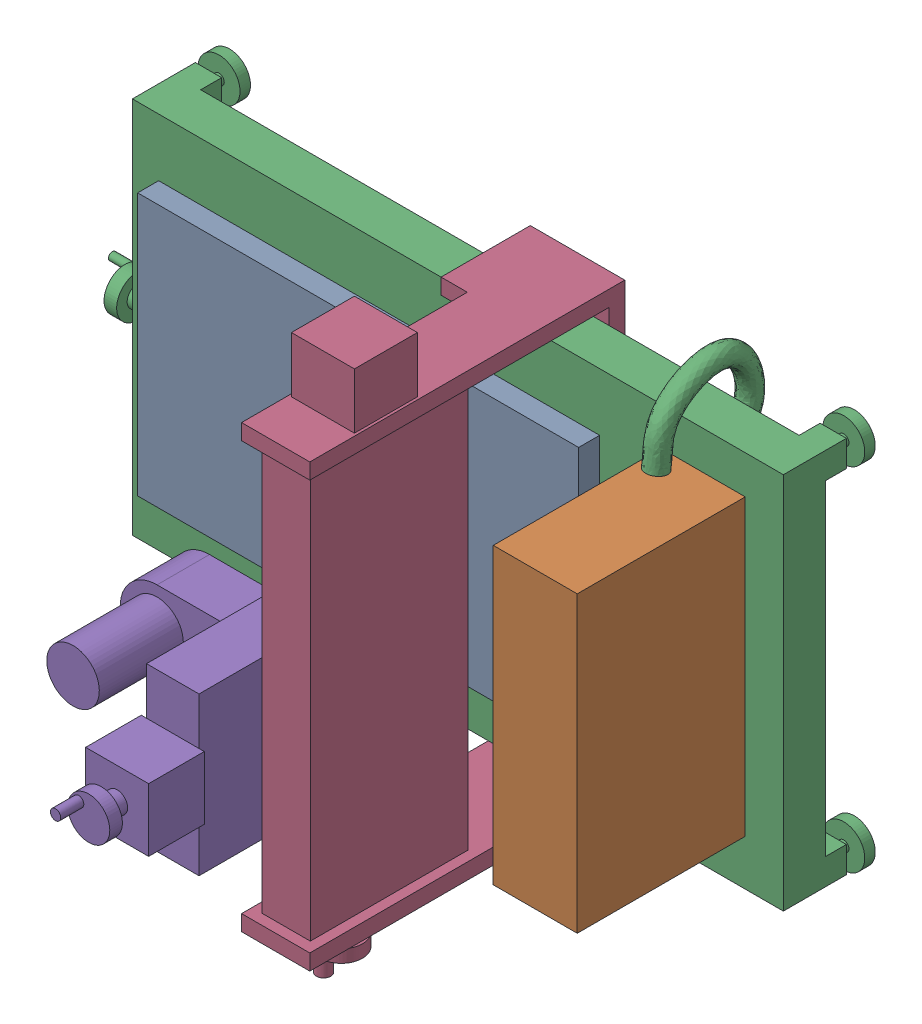
SolidWorks assembly RZ420, configuration ﾃﾞﾌｫﾙﾄ. Lengths in mm.
Overall size (727.03 522 505.06).
5 component instances, 5 part files, 12 mates.
Components (placement in the parent):
- base_RZ420-1: base_RZ420 [ﾃﾞﾌｫﾙﾄ] at (-219.6241 -100.9703 0) size (420 250 20)
- computer_RZ420-1: computer_RZ420 [ﾃﾞﾌｫﾙﾄ] at (259.0566 167.601 160) x (0 0 -1) z (0 -1 0) size (160 80 280)
- Part2_RZ420-1: Part2_RZ420 [ﾃﾞﾌｫﾙﾄ] at (375.3759 -155.9703 0) x (-1 0 0) z (0 0 -1) size (676.5 406.66 111.06)
- Part4_RZ420-1: Part4_RZ420 [ﾃﾞﾌｫﾙﾄ] at (79.3358 -170.9703 -55) x (1 0 0) z (0 -1 0) size (90 300 522)
- part3_RZ420-1: part3_RZ420 [ﾃﾞﾌｫﾙﾄ] at (-6.1642 39.9134 55) x (1 0 0) z (0 -1 0) size (190 342 150)
Mates (geometry in assembly coordinates):
- 一致1: coincident anti-aligned: plane of base_RZ420-1 through (-219.6241 -100.9703 0) normal (0 0 -1); plane of Part2_RZ420-1 through (375.3759 -155.9703 0) normal (0 0 1)
- 一致2: coincident anti-aligned: plane of computer_RZ420-1 through (259.0566 -112.399 0) normal (0 0 -1); plane of Part2_RZ420-1 through (375.3759 -155.9703 0) normal (0 0 1)
- 平行1: parallel anti-aligned: plane of computer_RZ420-1 through (259.0566 -112.399 160) normal (-1 0 0); plane of Part2_RZ420-1 through (375.3759 -155.9703 -40) normal (1 0 0)
- 平行3: parallel aligned: plane of Part2_RZ420-1 through (375.3759 -155.9703 -40) normal (0 0 -1); plane of Part4_RZ420-1 through (79.3358 -185.9703 -55) normal (0 0 -1)
- 平行4: parallel anti-aligned: plane of computer_RZ420-1 through (259.0566 -112.399 160) normal (-1 0 0); plane of Part4_RZ420-1 through (159.8358 219.0297 235) normal (1 0 0)
- 一致4: coincident anti-aligned: plane of Part4_RZ420-1 through (113.8358 219.0297 235) normal (-1 0 0); plane of part3_RZ420-1 through (113.8358 -110.0866 55) normal (1 0 0)
- 平行5: parallel aligned: plane of Part4_RZ420-1 through (159.8358 219.0297 85) normal (0 0 -1); plane of part3_RZ420-1 through (-6.1642 -110.0866 55) normal (0 0 -1)
- 一致5: coincident anti-aligned: plane of Part2_RZ420-1 through (375.3759 -155.9703 -40) normal (0 0 -1); plane of Part4_RZ420-1 through (79.3358 -212.9723 -40) normal (0 0 1)
- 距離1: distance = 15 mm anti-aligned: plane of Part4_RZ420-1 through (79.3358 219.0297 -55) normal (0 -1 0); plane of Part2_RZ420-1 through (375.3759 204.0297 -40) normal (0 1 0)
- 距離2: distance = 60 mm aligned: plane of part3_RZ420-1 through (63.8358 -110.0866 295) normal (0 0 1); plane of Part4_RZ420-1 through (159.8358 219.0297 235) normal (0 0 1)
- 距離3: distance = 25 mm aligned: plane of base_RZ420-1 through (-219.6241 -100.9703 20) normal (-1 0 0); plane of Part2_RZ420-1 through (-244.6241 -155.9703 -40) normal (-1 0 0)
- 距離4: distance = 55 mm aligned: plane of base_RZ420-1 through (-219.6241 -100.9703 20) normal (0 -1 0); plane of Part2_RZ420-1 through (375.3759 -155.9703 -40) normal (0 -1 0)
